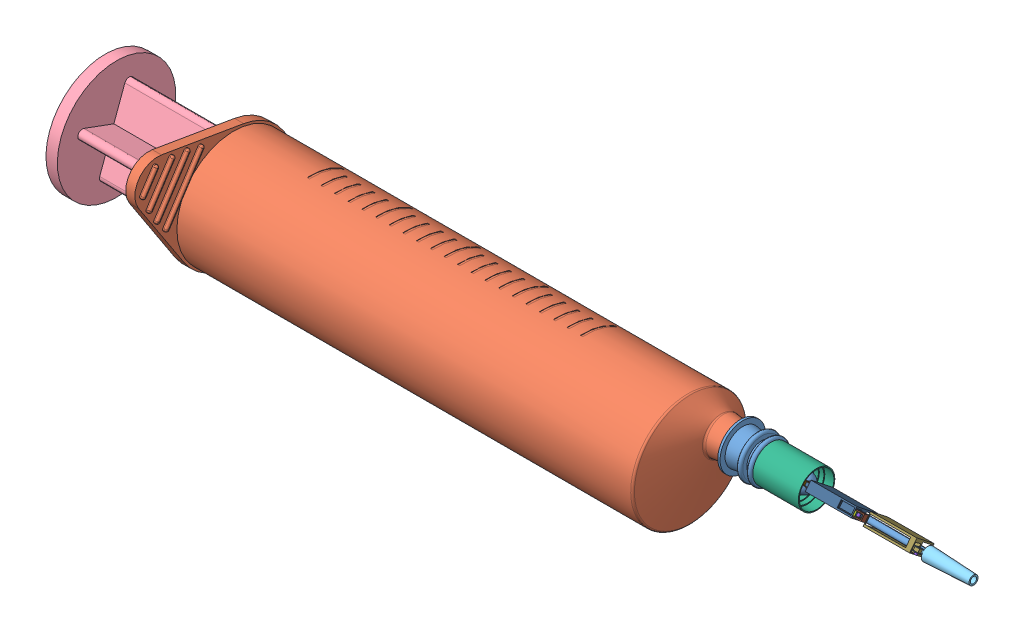
SolidWorks assembly final, configuration Default. Lengths in mm.
Overall size (188.34 49.15 56.07).
14 component instances, 12 part files, 28 mates.
Components (placement in the parent):
- needle final-1: needle final [Default] at (9.5452 29.325 39.3313) x (1 0 0) z (0 0.22483 -0.974398) size (47.46 10 10)
- pakka syringe-1: pakka syringe [Default] at (-114.4111 24.3065 42.6199) x (0 0.548094 0.836417) z (-1 0 0) size (50 26 121)
- pakka plunger rubber-1: pakka plunger rubber [Default] at (-26.2946 24.3065 42.6199) x (0 1 0.000261) z (0 -0.000261 1) size (22 8.85 22)
- pakka wala plunger-1: pakka wala plunger [Default] at (-30.1483 24.3065 42.6199) x (0 -0.938498 0.345285) z (0 -0.345285 -0.938498) size (26 111.5 26)
- needle part1-1: needle part1 [Default] at (36.6927 29.6784 39.0527) x (1 0 0) z (0 0.619064 0.78534) size (11 2.9 4.42)
- needle part-2: needle part [Default] at (12.2452 29.325 39.3313) x (0 0.619064 0.78534) z (-1 0 0) size (8 8 10.1)
- big link-1: big link [Default] at (24.851 32.4271 42.7013) x (-0.789241 0.380157 0.482265) z (-0.614084 -0.488591 -0.619822) size (1.6 0.9 1)
- pin2-3: pin2 [Default] at (13.0952 32.2677 41.3683) x (-0.694433 0.445452 0.565097) z (0 -0.78534 0.619064) size (0.6 0.6 1.3)
- pin2-5: pin2 [Default] at (24.5439 32.6933 41.989) x (0.568107 -0.509462 -0.6463) z (0 -0.78534 0.619064) size (0.6 0.6 1.3)
- pin2-7: pin2 [Default] at (36.189 31.0246 40.7605) x (0.102589 -0.615798 -0.781197) z (0 -0.78534 0.619064) size (0.6 0.6 1.3)
- pinlink-1: pinlink [Default] at (12.2452 31.8011 41.0994) x (1 0 0) z (0 0.619064 0.78534) size (1.6 0.9 1)
- Part1-1: Part1 [Default] at (23.6055 33.028 41.8482) x (-0.999935 0.007052 0.008946) z (0 -0.78534 0.619064) size (11 6 2)
- pinlink2-1: pinlink2 [Default] at (25.8588 33.0065 42.3863) x (-0.111953 -0.615173 -0.780403) z (-0.993714 0.069306 0.087921) size (1.3 1.3 1.7)
- Part2-1: Part2 [Default] at (13.189 30.8652 42.8198) x (0.9997 -0.015155 -0.019225) z (0 0.78534 -0.619064) size (11 5 2.6)
Mates (geometry in assembly coordinates):
- Concentric8: concentric anti-aligned: cylinder of pakka plunger rubber-1 through (-30.2983 24.3065 42.6199) axis (1 0 0) radius 6; cylinder of pakka wala plunger-1 through (-36.1483 24.3065 42.6199) axis (-1 0 0) radius 7.5
- Concentric9: concentric anti-aligned: cylinder of pakka syringe-1 through (-141.0737 24.3065 42.6199) axis (-1 0 0) radius 11; cylinder of pakka plunger rubber-1 through (-26.2946 24.3065 42.6199) axis (1 0 0) radius 11
- Coincident9: coincident anti-aligned: plane of pakka plunger rubber-1 through (-35.1483 24.3065 42.6199) normal (-1 0 0); plane of pakka wala plunger-1 through (-35.1483 18.6755 44.6916) normal (1 0 0)
- Concentric10: concentric aligned: cone of needle final-1 through (-4.4548 29.325 39.3313) axis (1 0 0); cone of pakka syringe-1 through (-8.4111 29.325 39.3313) axis (1 0 0)
- LimitDistance5: limit distance = 78.2628 mm aligned: plane of pakka syringe-1 through (-114.4111 17.1813 31.7465) normal (-1 0 0); plane of pakka wala plunger-1 through (-36.1483 14.9215 46.0727) normal (-1 0 0)
- Concentric11: concentric aligned: cylinder of needle final-1 through (48.5452 29.325 39.3313) axis (-1 0 0) radius 0.625; circle of needle part1-1
- Concentric18: concentric anti-aligned: cone of needle final-1 through (9.5452 29.325 39.3313) axis (1 0 0); cylinder of needle part-2 through (9.2452 29.325 39.3313) axis (-1 0 0) radius 3
- Concentric28: concentric aligned: cylinder of big link-1 through (24.5439 31.7509 42.7318) axis (0 0.78534 -0.619064) radius 0.3; cylinder of pin2-5 through (24.5439 31.6723 42.7937) axis (0 0.78534 -0.619064) radius 0.3
- Concentric52: concentric aligned: cylinder of needle part1-1 through (36.189 30.2392 41.3796) axis (0 0.78534 -0.619064) radius 0.3; cylinder of pin2-7 through (36.189 30.0036 41.5653) axis (0 0.78534 -0.619064) radius 0.3
- Concentric53: concentric aligned: cylinder of needle part1-1 through (36.189 30.2392 41.3796) axis (0 0.78534 -0.619064) radius 0.3; cylinder of pin2-7 through (36.189 30.0036 41.5653) axis (0 0.78534 -0.619064) radius 0.3
- Coincident85: coincident aligned: plane of needle part1-1 through (35.6927 29.6784 39.0527) normal (0 0.78534 -0.619064); plane of pin2-7 through (36.189 31.0246 40.7605) normal (0 0.78534 -0.619064)
- Coincident86: coincident anti-aligned: plane of needle final-1 through (2.2452 25.4274 38.432) normal (1 0 0); plane of needle part-2 through (2.2452 29.325 39.3313) normal (-1 0 0)
- Concentric61: concentric aligned: cylinder of pin2-3 through (13.0952 31.2467 42.173) axis (0 0.78534 -0.619064) radius 0.3; cylinder of pinlink-1 through (13.0952 31.3252 42.1111) axis (0 0.78534 -0.619064) radius 0.3
- Concentric62: concentric anti-aligned: cylinder of pin2-3 through (13.0952 31.2467 42.173) axis (0 0.78534 -0.619064) radius 0.3; cylinder of Part1-1 through (13.0952 32.2677 41.3683) axis (0 -0.78534 0.619064) radius 0.3
- Coincident91: coincident anti-aligned: plane of pinlink-1 through (12.3452 32.3416 41.9466) normal (0 -0.78534 0.619064); plane of Part1-1 through (12.5906 31.788 41.2443) normal (0 0.78534 -0.619064)
- Coincident92: coincident aligned: line of big link-1 through (23.6055 31.8892 42.7458) axis (0 0.78534 -0.619064); line of Part1-1 through (23.6055 31.4573 43.0863) axis (0 0.78534 -0.619064)
- Coincident96: coincident anti-aligned: plane of big link-1 through (24.8683 31.9878 41.417) normal (0 0.78534 -0.619064); plane of pinlink2-1 through (26.1569 32.8286 42.4838) normal (0 -0.78534 0.619064)
- Coincident98: coincident aligned: plane of pin2-5 through (24.5439 32.6933 41.989) normal (0 0.78534 -0.619064); plane of pinlink2-1 through (25.5146 32.2206 41.3894) normal (0 0.78534 -0.619064)
- Concentric67: concentric anti-aligned: cylinder of pin2-5 through (24.5439 31.6723 42.7937) axis (0 0.78534 -0.619064) radius 0.3; cylinder of pinlink2-1 through (24.5439 32.6933 41.989) axis (0 -0.78534 0.619064) radius 0.3
- Distance2: distance = 0.55 mm aligned: plane of Part1-1 through (23.6055 33.028 41.8482) normal (0 0.78534 -0.619064); plane of big link-1 through (24.8683 31.9878 41.417) normal (0 0.78534 -0.619064)
- Distance4: distance = 0.2 mm aligned: plane of pin2-3 through (13.0952 32.2677 41.3683) normal (0 0.78534 -0.619064); plane of pinlink-1 through (12.2452 32.4201 41.8847) normal (0 0.78534 -0.619064)
- Concentric68: concentric aligned: cylinder of pin2-7 through (36.189 30.0036 41.5653) axis (0 0.78534 -0.619064) radius 0.3; cylinder of Part2-1 through (36.189 30.1607 41.4415) axis (0 0.78534 -0.619064) radius 0.3
- Coincident99: coincident anti-aligned: plane of needle part1-1 through (35.6927 30.5127 40.2727) normal (0 -0.78534 0.619064); plane of Part2-1 through (36.696 31.1768 41.1152) normal (0 0.78534 -0.619064)
- Coincident100: coincident anti-aligned: line of pinlink2-1 through (25.7133 32.2068 41.3718) axis (0 -0.78534 0.619064); line of Part2-1 through (25.7133 30.6754 42.579) axis (0 0.78534 -0.619064)
- Distance9: distance = 0.65 mm aligned: plane of Part2-1 through (25.5419 28.3851 35.4737) normal (0 0.78534 -0.619064); plane of pinlink2-1 through (25.5146 32.2206 41.3894) normal (0 0.78534 -0.619064)
- Coincident101: coincident anti-aligned: plane of needle part-2 through (12.2452 29.325 39.3313) normal (1 0 0); plane of pinlink-1 through (12.2452 32.4201 41.8847) normal (-1 0 0)
- Parallel1: parallel anti-aligned: plane of needle part-2 through (12.3452 32.3301 41.9557) normal (0 -0.78534 0.619064); plane of pinlink-1 through (12.2452 32.4201 41.8847) normal (0 0.78534 -0.619064)
- Coincident103: coincident aligned: plane of needle part-2 through (12.3452 32.3723 41.9224) normal (0 0.619064 0.78534); plane of pinlink-1 through (12.2452 32.4201 41.8847) normal (0 0.619064 0.78534)
